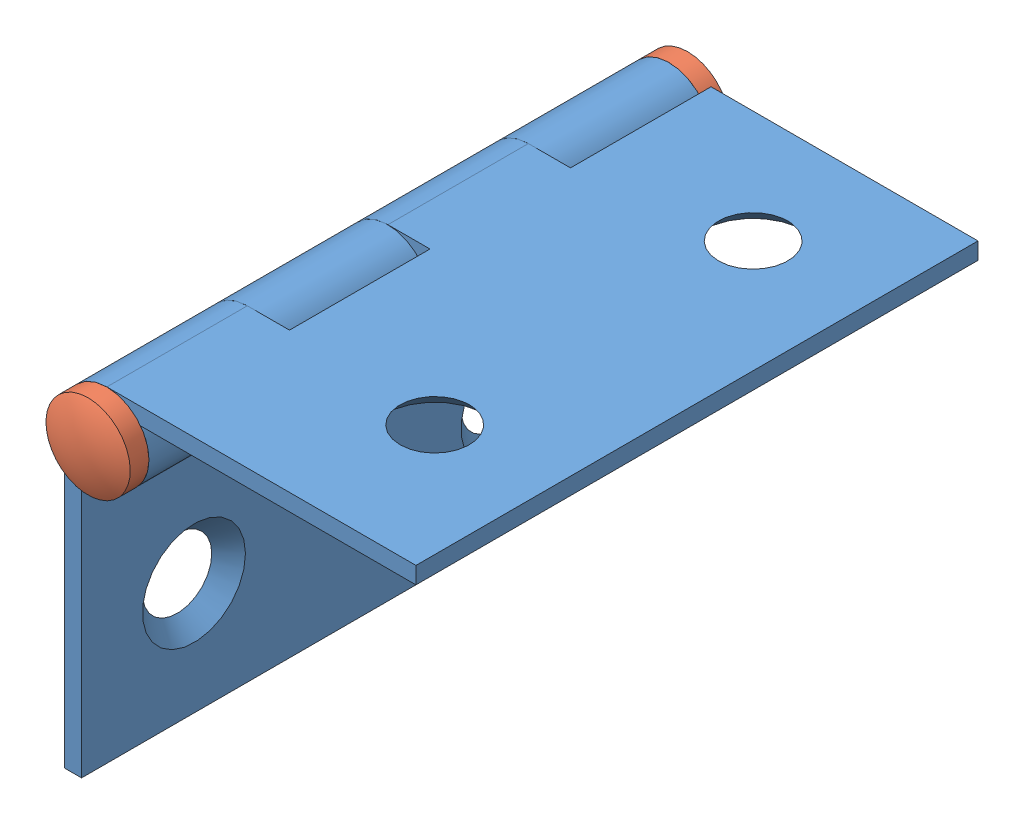
SolidWorks assembly Cerniera, configuration Default. Lengths in mm.
Overall size (18.75 18.75 33).
3 component instances, 2 part files, 6 mates.
Components (placement in the parent):
- ElementoCerniera-1: ElementoCerniera [Default] at (-4.7714 -11.2422 -5.2355) size (4.5 18.75 30)
- ElementoCerniera-2: ElementoCerniera [Default] at (13.9786 7.5078 -5.2355) x (0 -1 0) z (0 0 -1) size (4.5 18.75 30)
- Parte1^Cerniera-1: Parte1^Cerniera [Default] at (13.9786 7.5078 9.7645) x (0 1 0) z (0 0 1) size (4.5 4.5 33) (virtual)
Mates (geometry in assembly coordinates):
- Cardine1: hinge aligned: cylinder of ElementoCerniera-1 through (-2.5214 5.2578 -20.2355) axis (0 0 1) radius 1.75; cylinder of ElementoCerniera-2 through (-2.5214 5.2578 9.7645) axis (0 0 -1) radius 1.75; plane of ElementoCerniera-2 through (13.9786 7.5078 9.7645) normal (0 0 1); plane of ElementoCerniera-1 through (-4.7714 -11.2422 9.7645) normal (0 0 1)
- SulPosto1: in place: plane of ? through (5.3572 -9.4133 9.7645) normal (0 0 1); plane of ? through (0 0 9.7645) normal (0 0 1); moOrthogonalPlaneRef_w of ? through (5.3572 -9.4133 9.7645) normal (0 0 1); plane of ? through (0 0 9.7645) normal (0 1 0); plane of ? through (5.3572 -9.4133 9.7645) normal (0 0 1); plane of ? through (0 0 9.7645) normal (1 0 0); plane of ElementoCerniera-2 through (13.9786 7.5078 9.7645) normal (0 0 1); unknown of Parte1^Cerniera-1
- Coincidente3: coincident aligned: plane of ElementoCerniera-2; plane of Parte1^Cerniera-1
- Coincidente4: coincident aligned: moOrthogonalPlaneRef_w of ElementoCerniera-2; plane of Parte1^Cerniera-1
- Coincidente5: coincident anti-aligned: moOrthogonalPlaneRef_w of ElementoCerniera-2 through (7.5078 9.7645 0) axis (-1 0 0); plane of Parte1^Cerniera-1
- Angolo1: planar angle = 1.570796 rad aligned: plane of ElementoCerniera-2 through (13.9786 7.5078 -20.2355) normal (0 1 0); plane of ElementoCerniera-1 through (-4.7714 -11.2422 9.7645) normal (-1 0 0)
